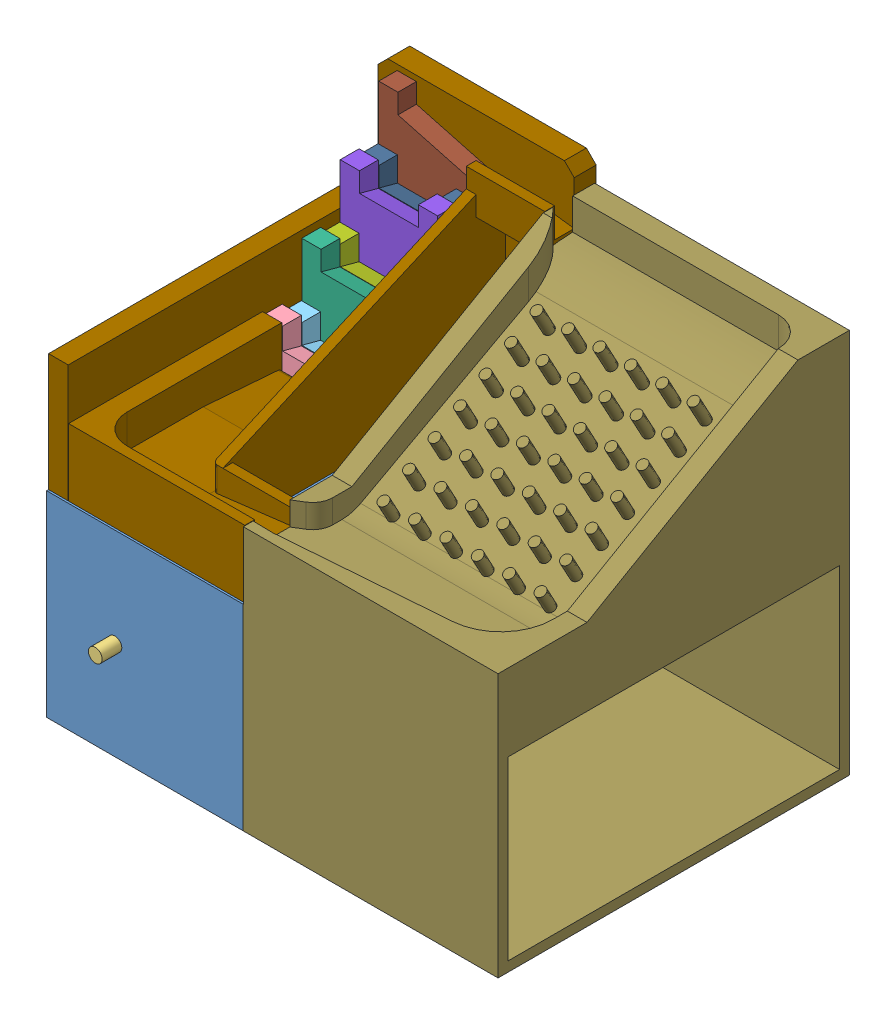
SolidWorks assembly 個人最終成品, configuration 默认. Lengths in mm.
Overall size (230 208.73 190.2).
12 component instances, 12 part files, 32 mates.
Components (placement in the parent):
- part-2: part [默认] at (-0.869 -50.4679 180) size (100 100 180)
- 凸輪-2: 凸輪 [默认] at (-15.869 -0.4679 180) x (-0.751026 -0.660273 0) z (0 0 -1) size (30 50 180)
- part9-2: part9 [默认] at (-15.869 -0.4679 270.2) size (7 7 10)
- 板塊1-1: 板塊1 [默认] at (-40.669 82.0423 160.2) size (49.6 60 9.6)
- 板塊2-1: 板塊2 [默认] at (-40.669 78.7018 150.4) size (49.6 71.68 9.6)
- 板塊3-1: 板塊3 [默认] at (-40.669 106.1523 140.6) size (49.6 84.11 9.6)
- 板塊4-1: 板塊4 [默认] at (-40.669 103.5618 130.8) size (49.6 96.54 9.6)
- 板塊5-1: 板塊5 [默认] at (-40.669 131.0123 121) size (49.6 108.97 9.6)
- 擋板-1: 擋板 [默认] at (-50.869 49.5321 90) size (100 108.73 179)
- 板塊6-2: 板塊6 [默认] at (-40.669 128.4218 111.3) size (49.6 121.4 9.4)
- 板塊7-2: 板塊7 [默认] at (-40.669 155.8723 101.6) size (49.6 133.83 9.4)
- 軌道-1: 軌道 [默认] at (49.131 -50.4679 91) x (0 0 1) z (-1 0 0) size (179 196.29 135)
Mates (geometry in assembly coordinates):
- 同心3: concentric aligned: cylinder of part-2 through (-15.869 -0.4679 90) axis (0 0 1) radius 3.25; cylinder of 凸輪-2 through (-15.869 -0.4679 90) axis (0 0 1) radius 3.125
- 重合3: coincident aligned: plane of part-2 through (-50.869 49.5321 90) normal (0 0 -1); plane of 凸輪-2 through (-15.869 -0.4679 90) normal (0 0 -1)
- 同心4: concentric anti-aligned: cylinder of 凸輪-2 through (-15.869 -0.4679 90) axis (0 0 1) radius 3.125; cylinder of part9-2 through (-15.869 -0.4679 280.2) axis (0 0 -1) radius 3.5
- 距离1: distance = 0.2 mm anti-aligned: plane of part9-2 through (-15.869 -0.4679 270.2) normal (0 0 -1); plane of part-2 through (-50.869 49.5321 270) normal (0 0 1)
- 距离2: distance = 0.2 mm anti-aligned: plane of part-2 through (-40.869 -40.4679 170) normal (0 0 -1); plane of 板塊1-1 through (-40.669 82.0423 169.8) normal (0 0 1)
- 距离3: distance = 0 mm anti-aligned: plane of 板塊1-1 through (-40.669 22.0423 169.8) normal (0 -1 0); cylinder of 凸輪-2 through (-22.4717 7.0423 168.7) axis (0 0 -1) radius 15
- 距离4: distance = 0.2 mm: plane of 板塊1-1 through (8.931 82.0423 169.8) normal (1 0 0); line of part-2 through (9.131 49.5321 170) axis (0 0 -1)
- 距离5: distance = 0.2 mm anti-aligned: plane of 板塊2-1 through (-40.669 78.7018 160) normal (0 0 1); plane of 板塊1-1 through (-40.669 82.0423 160.2) normal (0 0 -1)
- 距离6: distance = 0.2 mm anti-aligned: plane of 板塊2-1 through (8.931 78.7018 160) normal (1 0 0); plane of part-2 through (9.131 -40.4679 101.4) normal (-1 0 0)
- 相切5: tangent anti-aligned: cylinder of 凸輪-2 through (-9.2663 -7.9782 159.5) axis (0 0 -1) radius 15; plane of 板塊2-1 through (-40.669 7.0218 160) normal (0 -1 0)
- 距离7: distance = 0.2 mm anti-aligned: plane of 板塊3-1 through (-40.669 106.1523 150.2) normal (0 0 1); plane of 板塊2-1 through (-40.669 78.7018 150.4) normal (0 0 -1)
- 距离8: distance = 0.2 mm anti-aligned: plane of 板塊3-1 through (8.931 106.1523 150.2) normal (1 0 0); plane of part-2 through (9.131 -40.4679 101.4) normal (-1 0 0)
- 相切6: tangent anti-aligned: cylinder of 凸輪-2 through (-22.4717 7.0423 148.2) axis (0 0 -1) radius 15; plane of 板塊3-1 through (-40.669 22.0423 150.2) normal (0 -1 0)
- 距离9: distance = 0.2 mm anti-aligned: plane of 板塊4-1 through (-40.669 103.5618 140.4) normal (0 0 1); plane of 板塊3-1 through (-40.669 106.1523 140.6) normal (0 0 -1)
- 距离10: distance = 0.2 mm anti-aligned: plane of 板塊4-1 through (-40.669 103.5618 140.4) normal (-1 0 0); plane of part-2 through (-40.869 -40.4679 101.4) normal (1 0 0)
- 相切7: tangent anti-aligned: cylinder of 凸輪-2 through (-9.2663 -7.9782 138) axis (0 0 -1) radius 15; plane of 板塊4-1 through (-40.669 7.0218 140.4) normal (0 -1 0)
- 距离11: distance = 0.2 mm anti-aligned: plane of 板塊5-1 through (-40.669 131.0123 130.6) normal (0 0 1); plane of 板塊4-1 through (-40.669 103.5618 130.8) normal (0 0 -1)
- 距离12: distance = 0.2 mm anti-aligned: plane of 板塊5-1 through (-40.669 131.0123 130.6) normal (-1 0 0); plane of part-2 through (-40.869 -40.4679 101.4) normal (1 0 0)
- 相切8: tangent anti-aligned: cylinder of 凸輪-2 through (-22.4717 7.0423 127.7) axis (0 0 -1) radius 15; plane of 板塊5-1 through (-40.669 22.0423 130.6) normal (0 -1 0)
- 重合19: coincident anti-aligned: plane of part-2 through (-0.869 49.5321 180) normal (0 1 0); plane of 擋板-1 through (-30.869 49.5321 170.2) normal (0 -1 0)
- 距离15: distance = 0.2 mm: plane of 擋板-1 through (-30.869 49.5321 170.2) normal (0 0 -1); plane of 板塊1-1 through (-40.669 82.0423 169.8) normal (0 0 1)
- 重合21: coincident aligned: plane of 擋板-1 through (-50.869 49.5321 101.2) normal (-1 0 0); plane of part-2 through (-50.869 49.5321 90) normal (-1 0 0)
- 重合24: coincident aligned: plane of part-2 through (-50.869 49.5321 90) normal (0 0 -1); plane of 擋板-1 through (-50.869 49.5321 90) normal (0 0 -1)
- 距离17: distance = 0.3 mm anti-aligned: plane of 板塊6-2 through (-40.669 128.4218 120.7) normal (0 0 1); plane of 板塊5-1 through (-40.669 131.0123 121) normal (0 0 -1)
- 距离18: distance = 0.2 mm anti-aligned: plane of 板塊6-2 through (8.931 128.4218 120.7) normal (1 0 0); plane of part-2 through (9.131 -40.4679 101.4) normal (-1 0 0)
- 相切11: tangent anti-aligned: cylinder of 凸輪-2 through (-9.2663 -7.9782 116.5) axis (0 0 -1) radius 15; plane of 板塊6-2 through (-40.669 7.0218 120.7) normal (0 -1 0)
- 距离19: distance = 0.3 mm anti-aligned: plane of 板塊7-2 through (-40.669 155.8723 111) normal (0 0 1); plane of 板塊6-2 through (-40.669 128.4218 111.3) normal (0 0 -1)
- 距离20: distance = 0.2 mm anti-aligned: plane of 板塊7-2 through (8.931 155.8723 111) normal (1 0 0); plane of part-2 through (9.131 -40.4679 101.4) normal (-1 0 0)
- 相切12: tangent anti-aligned: cylinder of 凸輪-2 through (-22.4717 7.0423 107.2) axis (0 0 -1) radius 15; plane of 板塊7-2 through (-40.669 22.0423 111) normal (0 -1 0)
- 重合28: coincident aligned: plane of part-2 through (-50.869 49.5321 270) normal (0 0 1); plane of 軌道-1 through (179.131 -50.4679 270) normal (0 0 1)
- 重合29: coincident aligned: plane of part-2 through (-0.869 -50.4679 180) normal (0 -1 0); plane of 軌道-1 through (179.131 -50.4679 91) normal (0 -1 0)
- 重合31: coincident anti-aligned: plane of part-2 through (49.131 49.5321 90) normal (1 0 0); plane of 軌道-1 through (49.131 -50.4679 91) normal (-1 0 0)
